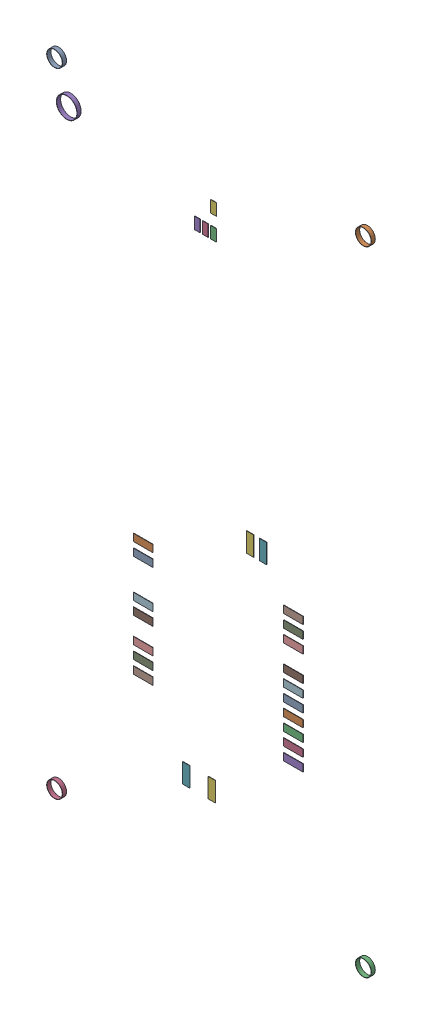
SolidWorks assembly NoNet, configuration Predeterminado. Lengths in mm.
Overall size (31.78 63.53 0.39).
90 component instances, 27 part files, 0 mates.
Components (placement in the parent):
- Pad Free-4(5.842mm,62.992mm) on Multi-Layer-1: Pad Free-4(5.842mm,62.992mm) on Multi-Layer [Predeterminado] at origin size (1.55 1.55 0.39)
  - Pad Hole-2-1: Pad Hole-2 [Predeterminado] at (5.842 62.992 -0.4013) size (1.55 1.55 0.39)
    - Pad Hole-Part-1-2-1: Pad Hole-Part-1-2 [Predeterminado] at origin size (1.55 1.55 0.39)
- Pad Free-4(36.068mm,62.992mm) on Multi-Layer-1: Pad Free-4(36.068mm,62.992mm) on Multi-Layer [Predeterminado] at origin size (1.55 1.55 0.39)
  - Pad Hole-2-1: Pad Hole-2 [Predeterminado] at (36.068 62.992 -0.4013) size (1.55 1.55 0.39)
    - Pad Hole-Part-1-2-1: Pad Hole-Part-1-2 [Predeterminado] at origin size (1.55 1.55 0.39)
- Pad Free-4(36.068mm,1.016mm) on Multi-Layer-1: Pad Free-4(36.068mm,1.016mm) on Multi-Layer [Predeterminado] at origin size (1.55 1.55 0.39)
  - Pad Hole-2-1: Pad Hole-2 [Predeterminado] at (36.068 1.016 -0.4013) size (1.55 1.55 0.39)
    - Pad Hole-Part-1-2-1: Pad Hole-Part-1-2 [Predeterminado] at origin size (1.55 1.55 0.39)
- Pad Free-4(5.842mm,1.016mm) on Multi-Layer-1: Pad Free-4(5.842mm,1.016mm) on Multi-Layer [Predeterminado] at origin size (1.55 1.55 0.39)
  - Pad Hole-2-1: Pad Hole-2 [Predeterminado] at (5.842 1.016 -0.4013) size (1.55 1.55 0.39)
    - Pad Hole-Part-1-2-1: Pad Hole-Part-1-2 [Predeterminado] at origin size (1.55 1.55 0.39)
- Pad U1-5(7.028mm,59.438mm) on Multi-Layer-1: Pad U1-5(7.028mm,59.438mm) on Multi-Layer [Predeterminado] at origin size (2.03 2.03 0.39)
  - Pad Hole-3-1: Pad Hole-3 [Predeterminado] at (7.0284 59.4378 -0.4013) size (2.03 2.03 0.39)
    - Pad Hole-Part-1-3-1: Pad Hole-Part-1-3 [Predeterminado] at origin size (2.03 2.03 0.39)
- Pad RAK4600-36(24.975mm,31.391mm) on Top Layer-1: Pad RAK4600-36(24.975mm,31.391mm) on Top Layer [Predeterminado] at origin size (0.7 1.9 0.04)
  - Pad RAK4600-36(24.975mm,31.391mm) on Top Layer-1-1: Pad RAK4600-36(24.975mm,31.391mm) on Top Layer-1 [Predeterminado] at (-68.317 -44.187 -0.0457) size (0.7 1.9 0.04)
    - Pad RAK4600-36(24.975mm,31.391mm) on Top Layer-Part-1-1: Pad RAK4600-36(24.975mm,31.391mm) on Top Layer-Part-1 [Predeterminado] at origin size (0.7 1.9 0.04)
- Pad RAK4600-35(26.225mm,31.391mm) on Top Layer-1: Pad RAK4600-35(26.225mm,31.391mm) on Top Layer [Predeterminado] at origin size (0.7 1.9 0.04)
  - Pad RAK4600-35(26.225mm,31.391mm) on Top Layer-1-1: Pad RAK4600-35(26.225mm,31.391mm) on Top Layer-1 [Predeterminado] at (-68.317 -44.187 -0.0457) size (0.7 1.9 0.04)
    - Pad RAK4600-35(26.225mm,31.391mm) on Top Layer-Part-1-1: Pad RAK4600-35(26.225mm,31.391mm) on Top Layer-Part-1 [Predeterminado] at origin size (0.7 1.9 0.04)
- Pad RAK4600-34(29.2mm,27.5mm) on Top Layer-1: Pad RAK4600-34(29.2mm,27.5mm) on Top Layer [Predeterminado] at origin size (1.9 0.7 0.04)
  - Pad RAK4600-34(29.2mm,27.5mm) on Top Layer-1-1: Pad RAK4600-34(29.2mm,27.5mm) on Top Layer-1 [Predeterminado] at (-68.317 -44.187 -0.0457) size (1.9 0.7 0.04)
    - Pad RAK4600-34(29.2mm,27.5mm) on Top Layer-Part-1-1: Pad RAK4600-34(29.2mm,27.5mm) on Top Layer-Part-1 [Predeterminado] at origin size (1.9 0.7 0.04)
- Pad RAK4600-33(29.2mm,26.25mm) on Top Layer-1: Pad RAK4600-33(29.2mm,26.25mm) on Top Layer [Predeterminado] at origin size (1.9 0.7 0.04)
  - Pad RAK4600-33(29.2mm,26.25mm) on Top Layer-1-1: Pad RAK4600-33(29.2mm,26.25mm) on Top Layer-1 [Predeterminado] at (-68.317 -44.187 -0.0457) size (1.9 0.7 0.04)
    - Pad RAK4600-33(29.2mm,26.25mm) on Top Layer-Part-1-1: Pad RAK4600-33(29.2mm,26.25mm) on Top Layer-Part-1 [Predeterminado] at origin size (1.9 0.7 0.04)
- Pad RAK4600-32(29.2mm,25mm) on Top Layer-1: Pad RAK4600-32(29.2mm,25mm) on Top Layer [Predeterminado] at origin size (1.9 0.7 0.04)
  - Pad RAK4600-32(29.2mm,25mm) on Top Layer-1-1: Pad RAK4600-32(29.2mm,25mm) on Top Layer-1 [Predeterminado] at (-68.317 -44.187 -0.0457) size (1.9 0.7 0.04)
    - Pad RAK4600-32(29.2mm,25mm) on Top Layer-Part-1-1: Pad RAK4600-32(29.2mm,25mm) on Top Layer-Part-1 [Predeterminado] at origin size (1.9 0.7 0.04)
- Pad RAK4600-30(29.2mm,22.5mm) on Top Layer-1: Pad RAK4600-30(29.2mm,22.5mm) on Top Layer [Predeterminado] at origin size (1.9 0.7 0.04)
  - Pad RAK4600-30(29.2mm,22.5mm) on Top Layer-1-1: Pad RAK4600-30(29.2mm,22.5mm) on Top Layer-1 [Predeterminado] at (-68.317 -44.187 -0.0457) size (1.9 0.7 0.04)
    - Pad RAK4600-30(29.2mm,22.5mm) on Top Layer-Part-1-1: Pad RAK4600-30(29.2mm,22.5mm) on Top Layer-Part-1 [Predeterminado] at origin size (1.9 0.7 0.04)
- Pad RAK4600-29(29.2mm,21.25mm) on Top Layer-1: Pad RAK4600-29(29.2mm,21.25mm) on Top Layer [Predeterminado] at origin size (1.9 0.7 0.04)
  - Pad RAK4600-29(29.2mm,21.25mm) on Top Layer-1-1: Pad RAK4600-29(29.2mm,21.25mm) on Top Layer-1 [Predeterminado] at (-68.317 -44.187 -0.0457) size (1.9 0.7 0.04)
    - Pad RAK4600-29(29.2mm,21.25mm) on Top Layer-Part-1-1: Pad RAK4600-29(29.2mm,21.25mm) on Top Layer-Part-1 [Predeterminado] at origin size (1.9 0.7 0.04)
- Pad RAK4600-28(29.2mm,20mm) on Top Layer-1: Pad RAK4600-28(29.2mm,20mm) on Top Layer [Predeterminado] at origin size (1.9 0.7 0.04)
  - Pad RAK4600-28(29.2mm,20mm) on Top Layer-1-1: Pad RAK4600-28(29.2mm,20mm) on Top Layer-1 [Predeterminado] at (-68.317 -44.187 -0.0457) size (1.9 0.7 0.04)
    - Pad RAK4600-28(29.2mm,20mm) on Top Layer-Part-1-1: Pad RAK4600-28(29.2mm,20mm) on Top Layer-Part-1 [Predeterminado] at origin size (1.9 0.7 0.04)
- Pad RAK4600-27(29.2mm,18.75mm) on Top Layer-1: Pad RAK4600-27(29.2mm,18.75mm) on Top Layer [Predeterminado] at origin size (1.9 0.7 0.04)
  - Pad RAK4600-27(29.2mm,18.75mm) on Top Layer-1-1: Pad RAK4600-27(29.2mm,18.75mm) on Top Layer-1 [Predeterminado] at (-68.317 -44.187 -0.0457) size (1.9 0.7 0.04)
    - Pad RAK4600-27(29.2mm,18.75mm) on Top Layer-Part-1-1: Pad RAK4600-27(29.2mm,18.75mm) on Top Layer-Part-1 [Predeterminado] at origin size (1.9 0.7 0.04)
- Pad RAK4600-26(29.2mm,17.5mm) on Top Layer-1: Pad RAK4600-26(29.2mm,17.5mm) on Top Layer [Predeterminado] at origin size (1.9 0.7 0.04)
  - Pad RAK4600-26(29.2mm,17.5mm) on Top Layer-1-1: Pad RAK4600-26(29.2mm,17.5mm) on Top Layer-1 [Predeterminado] at (-68.317 -44.187 -0.0457) size (1.9 0.7 0.04)
    - Pad RAK4600-26(29.2mm,17.5mm) on Top Layer-Part-1-1: Pad RAK4600-26(29.2mm,17.5mm) on Top Layer-Part-1 [Predeterminado] at origin size (1.9 0.7 0.04)
- Pad RAK4600-25(29.2mm,16.25mm) on Top Layer-1: Pad RAK4600-25(29.2mm,16.25mm) on Top Layer [Predeterminado] at origin size (1.9 0.7 0.04)
  - Pad RAK4600-25(29.2mm,16.25mm) on Top Layer-1-1: Pad RAK4600-25(29.2mm,16.25mm) on Top Layer-1 [Predeterminado] at (-68.317 -44.187 -0.0457) size (1.9 0.7 0.04)
    - Pad RAK4600-25(29.2mm,16.25mm) on Top Layer-Part-1-1: Pad RAK4600-25(29.2mm,16.25mm) on Top Layer-Part-1 [Predeterminado] at origin size (1.9 0.7 0.04)
- Pad RAK4600-24(29.2mm,15mm) on Top Layer-1: Pad RAK4600-24(29.2mm,15mm) on Top Layer [Predeterminado] at origin size (1.9 0.7 0.04)
  - Pad RAK4600-24(29.2mm,15mm) on Top Layer-1-1: Pad RAK4600-24(29.2mm,15mm) on Top Layer-1 [Predeterminado] at (-68.317 -44.187 -0.0457) size (1.9 0.7 0.04)
    - Pad RAK4600-24(29.2mm,15mm) on Top Layer-Part-1-1: Pad RAK4600-24(29.2mm,15mm) on Top Layer-Part-1 [Predeterminado] at origin size (1.9 0.7 0.04)
- Pad RAK4600-17(21.225mm,8.691mm) on Top Layer-1: Pad RAK4600-17(21.225mm,8.691mm) on Top Layer [Predeterminado] at origin size (0.7 1.9 0.04)
  - Pad RAK4600-17(21.225mm,8.691mm) on Top Layer-1-1: Pad RAK4600-17(21.225mm,8.691mm) on Top Layer-1 [Predeterminado] at (-68.317 -44.187 -0.0457) size (0.7 1.9 0.04)
    - Pad RAK4600-17(21.225mm,8.691mm) on Top Layer-Part-1-1: Pad RAK4600-17(21.225mm,8.691mm) on Top Layer-Part-1 [Predeterminado] at origin size (0.7 1.9 0.04)
- Pad RAK4600-15(18.725mm,8.691mm) on Top Layer-1: Pad RAK4600-15(18.725mm,8.691mm) on Top Layer [Predeterminado] at origin size (0.7 1.9 0.04)
  - Pad RAK4600-15(18.725mm,8.691mm) on Top Layer-1-1: Pad RAK4600-15(18.725mm,8.691mm) on Top Layer-1 [Predeterminado] at (-68.317 -44.187 -0.0457) size (0.7 1.9 0.04)
    - Pad RAK4600-15(18.725mm,8.691mm) on Top Layer-Part-1-1: Pad RAK4600-15(18.725mm,8.691mm) on Top Layer-Part-1 [Predeterminado] at origin size (0.7 1.9 0.04)
- Pad RAK4600-11(14.5mm,15mm) on Top Layer-1: Pad RAK4600-11(14.5mm,15mm) on Top Layer [Predeterminado] at origin size (1.9 0.7 0.04)
  - Pad RAK4600-11(14.5mm,15mm) on Top Layer-1-1: Pad RAK4600-11(14.5mm,15mm) on Top Layer-1 [Predeterminado] at (-68.317 -44.187 -0.0457) size (1.9 0.7 0.04)
    - Pad RAK4600-11(14.5mm,15mm) on Top Layer-Part-1-1: Pad RAK4600-11(14.5mm,15mm) on Top Layer-Part-1 [Predeterminado] at origin size (1.9 0.7 0.04)
- Pad RAK4600-10(14.5mm,16.25mm) on Top Layer-1: Pad RAK4600-10(14.5mm,16.25mm) on Top Layer [Predeterminado] at origin size (1.9 0.7 0.04)
  - Pad RAK4600-10(14.5mm,16.25mm) on Top Layer-1-1: Pad RAK4600-10(14.5mm,16.25mm) on Top Layer-1 [Predeterminado] at (-68.317 -44.187 -0.0457) size (1.9 0.7 0.04)
    - Pad RAK4600-10(14.5mm,16.25mm) on Top Layer-Part-1-1: Pad RAK4600-10(14.5mm,16.25mm) on Top Layer-Part-1 [Predeterminado] at origin size (1.9 0.7 0.04)
- Pad RAK4600-9(14.5mm,17.5mm) on Top Layer-1: Pad RAK4600-9(14.5mm,17.5mm) on Top Layer [Predeterminado] at origin size (1.9 0.7 0.04)
  - Pad RAK4600-9(14.5mm,17.5mm) on Top Layer-1-1: Pad RAK4600-9(14.5mm,17.5mm) on Top Layer-1 [Predeterminado] at (-68.317 -44.187 -0.0457) size (1.9 0.7 0.04)
    - Pad RAK4600-9(14.5mm,17.5mm) on Top Layer-Part-1-1: Pad RAK4600-9(14.5mm,17.5mm) on Top Layer-Part-1 [Predeterminado] at origin size (1.9 0.7 0.04)
- Pad RAK4600-7(14.5mm,20mm) on Top Layer-1: Pad RAK4600-7(14.5mm,20mm) on Top Layer [Predeterminado] at origin size (1.9 0.7 0.04)
  - Pad RAK4600-7(14.5mm,20mm) on Top Layer-1-1: Pad RAK4600-7(14.5mm,20mm) on Top Layer-1 [Predeterminado] at (-68.317 -44.187 -0.0457) size (1.9 0.7 0.04)
    - Pad RAK4600-7(14.5mm,20mm) on Top Layer-Part-1-1: Pad RAK4600-7(14.5mm,20mm) on Top Layer-Part-1 [Predeterminado] at origin size (1.9 0.7 0.04)
- Pad RAK4600-6(14.5mm,21.25mm) on Top Layer-1: Pad RAK4600-6(14.5mm,21.25mm) on Top Layer [Predeterminado] at origin size (1.9 0.7 0.04)
  - Pad RAK4600-6(14.5mm,21.25mm) on Top Layer-1-1: Pad RAK4600-6(14.5mm,21.25mm) on Top Layer-1 [Predeterminado] at (-68.317 -44.187 -0.0457) size (1.9 0.7 0.04)
    - Pad RAK4600-6(14.5mm,21.25mm) on Top Layer-Part-1-1: Pad RAK4600-6(14.5mm,21.25mm) on Top Layer-Part-1 [Predeterminado] at origin size (1.9 0.7 0.04)
- Pad RAK4600-3(14.5mm,25mm) on Top Layer-1: Pad RAK4600-3(14.5mm,25mm) on Top Layer [Predeterminado] at origin size (1.9 0.7 0.04)
  - Pad RAK4600-3(14.5mm,25mm) on Top Layer-1-1: Pad RAK4600-3(14.5mm,25mm) on Top Layer-1 [Predeterminado] at (-68.317 -44.187 -0.0457) size (1.9 0.7 0.04)
    - Pad RAK4600-3(14.5mm,25mm) on Top Layer-Part-1-1: Pad RAK4600-3(14.5mm,25mm) on Top Layer-Part-1 [Predeterminado] at origin size (1.9 0.7 0.04)
- Pad RAK4600-2(14.5mm,26.25mm) on Top Layer-1: Pad RAK4600-2(14.5mm,26.25mm) on Top Layer [Predeterminado] at origin size (1.9 0.7 0.04)
  - Pad RAK4600-2(14.5mm,26.25mm) on Top Layer-1-1: Pad RAK4600-2(14.5mm,26.25mm) on Top Layer-1 [Predeterminado] at (-68.317 -44.187 -0.0457) size (1.9 0.7 0.04)
    - Pad RAK4600-2(14.5mm,26.25mm) on Top Layer-Part-1-1: Pad RAK4600-2(14.5mm,26.25mm) on Top Layer-Part-1 [Predeterminado] at origin size (1.9 0.7 0.04)
- Pad ADXL345-11(21.4mm,55.903mm) on Top Layer-1: Pad ADXL345-11(21.4mm,55.903mm) on Top Layer [Predeterminado] at origin size (0.55 1.15 0.04)
  - Pad ADXL345-11(21.4mm,55.903mm) on Top Layer-1-1: Pad ADXL345-11(21.4mm,55.903mm) on Top Layer-1 [Predeterminado] at (-68.317 -44.187 -0.0457) size (0.55 1.15 0.04)
    - Pad ADXL345-11(21.4mm,55.903mm) on Top Layer-Part-1-1: Pad ADXL345-11(21.4mm,55.903mm) on Top Layer-Part-1 [Predeterminado] at origin size (0.55 1.15 0.04)
- Pad ADXL345-10(20.6mm,55.903mm) on Top Layer-1: Pad ADXL345-10(20.6mm,55.903mm) on Top Layer [Predeterminado] at origin size (0.55 1.15 0.04)
  - Pad ADXL345-10(20.6mm,55.903mm) on Top Layer-1-1: Pad ADXL345-10(20.6mm,55.903mm) on Top Layer-1 [Predeterminado] at (-68.317 -44.187 -0.0457) size (0.55 1.15 0.04)
    - Pad ADXL345-10(20.6mm,55.903mm) on Top Layer-Part-1-1: Pad ADXL345-10(20.6mm,55.903mm) on Top Layer-Part-1 [Predeterminado] at origin size (0.55 1.15 0.04)
- Pad ADXL345-9(19.8mm,55.903mm) on Top Layer-1: Pad ADXL345-9(19.8mm,55.903mm) on Top Layer [Predeterminado] at origin size (0.55 1.15 0.04)
  - Pad ADXL345-9(19.8mm,55.903mm) on Top Layer-1-1: Pad ADXL345-9(19.8mm,55.903mm) on Top Layer-1 [Predeterminado] at (-68.317 -44.187 -0.0457) size (0.55 1.15 0.04)
    - Pad ADXL345-9(19.8mm,55.903mm) on Top Layer-Part-1-1: Pad ADXL345-9(19.8mm,55.903mm) on Top Layer-Part-1 [Predeterminado] at origin size (0.55 1.15 0.04)
- Pad ADXL345-3(21.4mm,58.097mm) on Top Layer-1: Pad ADXL345-3(21.4mm,58.097mm) on Top Layer [Predeterminado] at origin size (0.55 1.15 0.04)
  - Pad ADXL345-3(21.4mm,58.097mm) on Top Layer-1-1: Pad ADXL345-3(21.4mm,58.097mm) on Top Layer-1 [Predeterminado] at (-68.317 -44.187 -0.0457) size (0.55 1.15 0.04)
    - Pad ADXL345-3(21.4mm,58.097mm) on Top Layer-Part-1-1: Pad ADXL345-3(21.4mm,58.097mm) on Top Layer-Part-1 [Predeterminado] at origin size (0.55 1.15 0.04)
